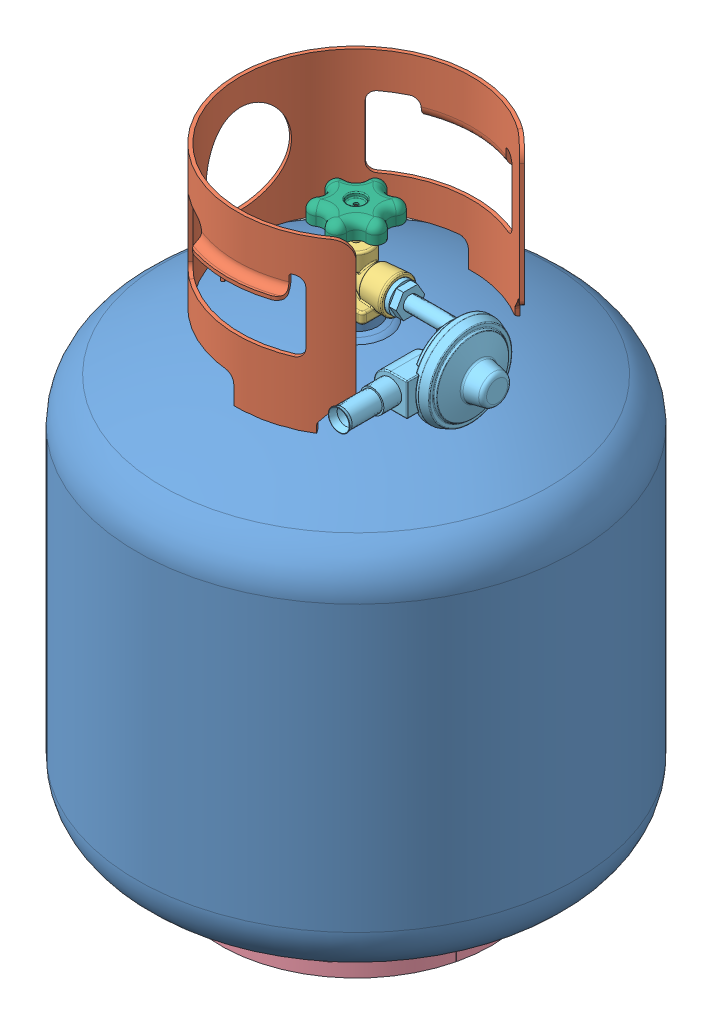
SolidWorks assembly User Library-BBQ Liquid Propane Tank Assembly, configuration Default. Lengths in mm.
Overall size (313.28 449.06 313.28).
6 component instances, 6 part files, 9 mates.
Components (placement in the parent):
- tank body2-1: tank body2 [Default] at origin size (313.28 351.71 313.28)
- tank_lifting_ring2-1: tank_lifting_ring2 [Default] at (0 393.7 0) x (1 0 0) z (0 -1 0) size (145.99 185 127.74)
- tank_valve_body2-1: tank_valve_body2 [Default] at (0 336.55 0) x (-1 0 0) z (0 0 -1) size (49.7 61.9 38.1)
- tank_support_ring2-1: tank_support_ring2 [Default] at (0 8.8817 0) x (0.972219 0 0.234072) z (0 1 0) size (193.55 193.55 25.4)
- regulator2-1: regulator2 [Default] at (96.0548 365.2992 23.8141) x (0 -1 0) z (0 0 1) size (63.5 109.79 108.79)
- gas_valve_knob2-1: gas_valve_knob2 [Default] at (0 409.9731 0) x (-0.96497 0 0.262361) z (0 -1 0) size (49.19 50.8 14.83)
Mates (geometry in assembly coordinates):
- Concentric2: concentric anti-aligned: cone of tank_valve_body2-1 through (28.4091 365.2992 0) axis (-1 0 0); cylinder of regulator2-1 through (30.6498 365.2992 0) axis (1 0 0) radius 10.414
- Coincident2: coincident anti-aligned: circle of tank_valve_body2-1; plane of regulator2-1 through (30.6498 365.2992 0) normal (-1 0 0)
- Concentric3: concentric aligned: cone of tank body2-1 through (0 351.7131 0) axis (0 -1 0); cone of tank_valve_body2-1 through (0 353.6861 0) axis (0 -1 0)
- Coincident3: coordinate: point of tank body2-1; point of assembly
- Concentric4: concentric anti-aligned: cylinder of tank body2-1 through (0 0 0) axis (0 -1 0) radius 156.6418; cylinder of tank_support_ring2-1 through (0 -607.2811 0) axis (0 1 0) radius 96.774
- Concentric5: concentric aligned: cylinder of tank body2-1 through (0 0 0) axis (0 -1 0) radius 156.6418; cylinder of tank_lifting_ring2-1 through (0 861.8261 0) axis (0 -1 0) radius 85.09
- Tangent1: tangent: face of tank body2-1; plane of tank_valve_body2-1 through (0 336.55 0) normal (0 -1 0)
- Parallel1: parallel anti-aligned: plane of tank_valve_body2-1 through (23.4929 352.0094 -19.05) normal (0 0 -1); plane of assembly
- Parallel2: parallel aligned: plane of regulator2-1 through (70.6548 371.4673 13.7348) normal (0 1 0); plane of assembly
